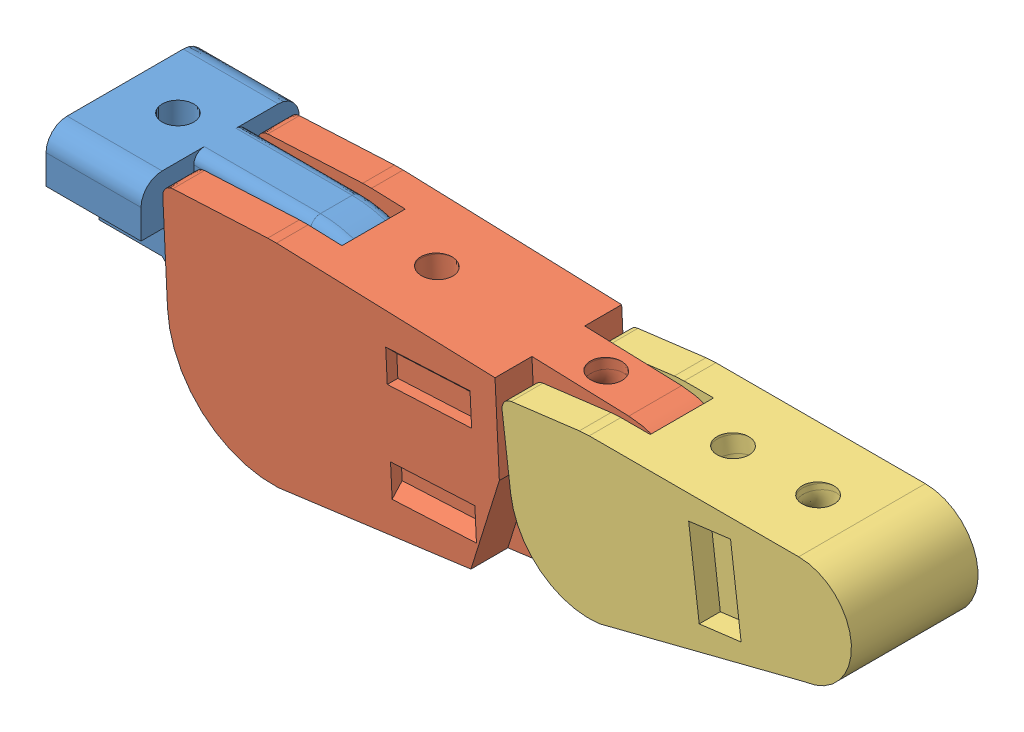
SolidWorks assembly rh4v4, configuration Default. Lengths in mm.
3 component instances, 3 part files, 6 mates.
Components (placement in the parent):
- robot hand v4 f4 4-1: robot hand v4 f4 4 [Default] at (21.3224 10.6534 23.7221) size (30 20 15)
- rhf4l1-1: rhf4l1 [Default] at (36.3037 11.4009 23.7221) x (0.998758 0.049833 0) z (0 0 1) size (47.5 20 12)
- rhf4l2-1: rhf4l2 [Default] at (61.2067 13.3984 23.7221) x (0.992157 0.125 0) z (0 0 1) size (32.5 15 12)
Mates (geometry in assembly coordinates):
- Concentric1: concentric anti-aligned: circle of robot hand v4 f4 4-1; cylinder of rhf4l1-1 through (21.3224 10.6534 29.7221) axis (0 0 -1) radius 2.5
- Concentric2: concentric aligned: cylinder of rhf4l1-1 through (51.2851 12.1484 28.2221) axis (0 0 -1) radius 3; cylinder of rhf4l2-1 through (51.2851 12.1484 29.7221) axis (0 0 -1) radius 2.5
- Width1: width: plane of robot hand v4 f4 4-1 through (21.3224 10.6534 26.2221) normal (0 0 1); plane of rhf4l1-1 through (21.3224 10.6534 21.2221) normal (0 0 -1); plane of robot hand v4 f4 4-1 through (36.3037 11.4009 26.7221) normal (0 0 -1); plane of rhf4l1-1 through (36.3037 11.4009 20.7221) normal (0 0 1)
- Width2: width: plane of rhf4l1-1 through (36.3037 11.4009 26.2221) normal (0 0 1); plane of rhf4l2-1 through (36.3037 11.4009 21.2221) normal (0 0 -1); plane of rhf4l1-1 through (61.2067 13.3984 26.7221) normal (0 0 -1); plane of rhf4l2-1 through (61.2067 13.3984 20.7221) normal (0 0 1)
- Coincident1: coincident aligned: plane of robot hand v4 f4 4-1 through (21.3224 20.6534 26.2221) normal (0 1 0); plane of rhf4l1-1 through (36.5975 20.1459 29.7221) normal (0.03357 0.999436 0)
- Coincident2: coincident aligned: plane of rhf4l1-1 through (36.5975 20.1459 29.7221) normal (0.03357 0.999436 0); plane of rhf4l2-1 through (61.2067 19.6484 29.7221) normal (0 1 0)
